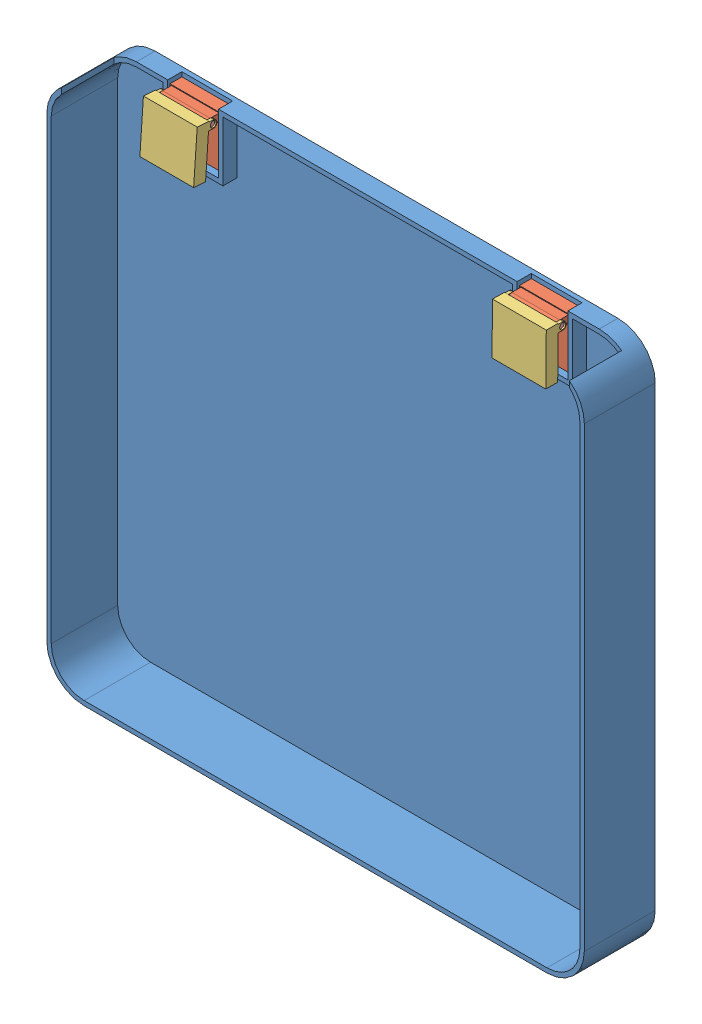
SolidWorks assembly Assemblage3, configuration Défaut. Lengths in mm.
Overall size (360 356 47.5).
7 component instances, 4 part files, 14 mates.
Components (placement in the parent):
- Lid-1: Lid [Défaut] at (-234.6697 -187.9854 -23.75) size (360 356 47.5)
- hinge1-1: hinge1 [Défaut] at (79.3303 165.0146 -20.75) x (-1 0 0) z (0 0 1) size (34 34 16.5)
- hinge1-2: hinge1 [Défaut] at (-154.6697 165.0146 -20.75) x (-1 0 0) z (0 0 1) size (34 34 16.5)
- hingeconnection-1: hingeconnection [Défaut] at (-189.6697 165.7763 4.0134) x (1 0 0) z (0 -0.06991 -0.997553) size (36 34 13.5)
- hingeconnection-2: hingeconnection [Défaut] at (44.3303 165.1271 4.2187) x (1 0 0) z (0 -0.010238 -0.999948) size (36 34 13.5)
- cylinderhinge-1: cylinderhinge [Défaut] at (-188.6697 162.0146 -6.75) x (0 0 -1) z (1 0 0) size (4 4 34)
- cylinderhinge-2: cylinderhinge [Défaut] at (45.3303 162.0146 -6.75) x (0 0 -1) z (1 0 0) size (4 4 34)
Mates (geometry in assembly coordinates):
- Coïncidente1: coincident anti-aligned: plane of Lid-1 through (-209.6697 143.0146 -20.75) normal (0 0 1); plane of hinge1-2 through (-154.6697 165.0146 -20.75) normal (0 0 -1)
- Distance1: distance = 3 mm anti-aligned: plane of Lid-1 through (-234.6697 128.0146 -11.25) normal (0 1 0); plane of hinge1-2 through (-154.6697 131.0146 -12.75) normal (0 -1 0)
- Coïncidente4: coincident anti-aligned: plane of Lid-1 through (-154.6697 -187.9854 -11.25) normal (-1 0 0); plane of hinge1-2 through (-154.6697 165.0146 -12.75) normal (1 0 0)
- Coïncidente5: coincident anti-aligned: plane of Lid-1 through (-209.6697 143.0146 -20.75) normal (0 0 1); plane of hinge1-1 through (79.3303 165.0146 -20.75) normal (0 0 -1)
- Distance3: distance = 3 mm anti-aligned: plane of hinge1-1 through (79.3303 131.0146 -12.75) normal (0 -1 0); plane of Lid-1 through (-234.6697 128.0146 -11.25) normal (0 1 0)
- Coïncidente8: coincident anti-aligned: plane of Lid-1 through (79.3303 -187.9854 -11.25) normal (-1 0 0); plane of hinge1-1 through (79.3303 165.0146 -12.75) normal (1 0 0)
- Coaxiale1: concentric anti-aligned: cylinder of hinge1-2 through (-187.6697 162.0146 -6.75) axis (1 0 0) radius 2; cylinder of cylinderhinge-1 through (-154.6697 162.0146 -6.75) axis (-1 0 0) radius 2
- Coaxiale2: concentric anti-aligned: cylinder of hinge1-1 through (46.3303 162.0146 -6.75) axis (1 0 0) radius 2; cylinder of cylinderhinge-2 through (79.3303 162.0146 -6.75) axis (-1 0 0) radius 2
- Distance4: distance = 1 mm aligned: plane of cylinderhinge-1 through (-188.6697 162.0146 -6.75) normal (-1 0 0); plane of hinge1-2 through (-187.6697 162.0146 -6.75) normal (-1 0 0)
- Distance5: distance = 1 mm aligned: plane of hinge1-1 through (46.3303 162.0146 -6.75) normal (-1 0 0); plane of cylinderhinge-2 through (45.3303 162.0146 -6.75) normal (-1 0 0)
- Coaxiale3: concentric aligned: cylinder of hingeconnection-1 through (-153.6697 162.0146 -6.75) axis (-1 0 0) radius 2; cylinder of cylinderhinge-1 through (-154.6697 162.0146 -6.75) axis (-1 0 0) radius 2
- Coïncidente11: coincident anti-aligned: plane of hinge1-2 through (-155.6697 162.0146 -6.75) normal (1 0 0); plane of hingeconnection-1 through (-155.6697 162.0146 -6.75) normal (-1 0 0)
- Coaxiale4: concentric aligned: cylinder of hingeconnection-2 through (80.3303 162.0146 -6.75) axis (-1 0 0) radius 2; cylinder of cylinderhinge-2 through (79.3303 162.0146 -6.75) axis (-1 0 0) radius 2
- Coïncidente12: coincident anti-aligned: plane of hinge1-1 through (46.3303 162.0146 -6.75) normal (-1 0 0); plane of hingeconnection-2 through (46.3303 162.0146 -6.75) normal (1 0 0)
